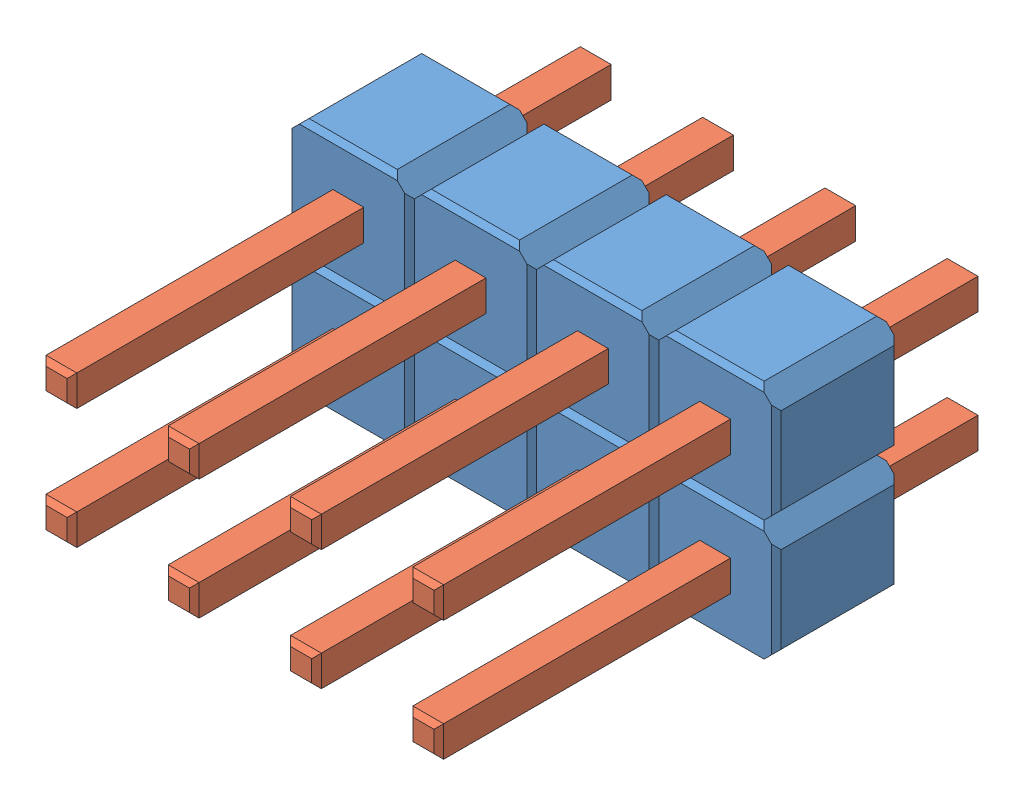
SolidWorks assembly Сборка14, configuration Default. Lengths in mm.
Overall size (10.16 5 11.3).
26 component instances, 2 part files, 2 mates.
Components (placement in the parent):
- pls_1x4_vert-1: pls_1x4_vert [Default] at (0.9139 -0.4526 1.8357) size (10.16 2.5 11.3)
  - pls_1_vert-1: pls_1_vert [Default] at (2.4589 -1.2488 -2.1291) size (2.54 2.5 11.3)
    - pin_plastic-1: pin_plastic [По умолчанию] at (1.6831 0.6372 -1.2507) size (2.54 2.5 2.54)
    - pin-1: pin [Default] at (-0.8569 0.6372 7.3493) x (1 0 0) z (0 1 0) size (0.64 11.3 0.64)
  - pls_1_vert-2: pls_1_vert [Default] at (-0.0811 -1.2488 -2.1291) size (2.54 2.5 11.3)
    - pin_plastic-1: pin_plastic [По умолчанию] at (1.6831 0.6372 -1.2507) size (2.54 2.5 2.54)
    - pin-1: pin [Default] at (-0.8569 0.6372 7.3493) x (1 0 0) z (0 1 0) size (0.64 11.3 0.64)
  - pls_1_vert-4: pls_1_vert [Default] at (-2.6211 -1.2488 -2.1291) size (2.54 2.5 11.3)
    - pin_plastic-1: pin_plastic [По умолчанию] at (1.6831 0.6372 -1.2507) size (2.54 2.5 2.54)
    - pin-1: pin [Default] at (-0.8569 0.6372 7.3493) x (1 0 0) z (0 1 0) size (0.64 11.3 0.64)
  - pls_1_vert-5: pls_1_vert [Default] at (-5.1611 -1.2488 -2.1291) size (2.54 2.5 11.3)
    - pin_plastic-1: pin_plastic [По умолчанию] at (1.6831 0.6372 -1.2507) size (2.54 2.5 2.54)
    - pin-1: pin [Default] at (-0.8569 0.6372 7.3493) x (1 0 0) z (0 1 0) size (0.64 11.3 0.64)
- pls_1x4_vert-2: pls_1x4_vert [Default] at (0.9139 2.0474 1.8357) size (10.16 2.5 11.3)
  - pls_1_vert-1: pls_1_vert [Default] at (2.4589 -1.2488 -2.1291) size (2.54 2.5 11.3)
    - pin_plastic-1: pin_plastic [По умолчанию] at (1.6831 0.6372 -1.2507) size (2.54 2.5 2.54)
    - pin-1: pin [Default] at (-0.8569 0.6372 7.3493) x (1 0 0) z (0 1 0) size (0.64 11.3 0.64)
  - pls_1_vert-2: pls_1_vert [Default] at (-0.0811 -1.2488 -2.1291) size (2.54 2.5 11.3)
    - pin_plastic-1: pin_plastic [По умолчанию] at (1.6831 0.6372 -1.2507) size (2.54 2.5 2.54)
    - pin-1: pin [Default] at (-0.8569 0.6372 7.3493) x (1 0 0) z (0 1 0) size (0.64 11.3 0.64)
  - pls_1_vert-4: pls_1_vert [Default] at (-2.6211 -1.2488 -2.1291) size (2.54 2.5 11.3)
    - pin_plastic-1: pin_plastic [По умолчанию] at (1.6831 0.6372 -1.2507) size (2.54 2.5 2.54)
    - pin-1: pin [Default] at (-0.8569 0.6372 7.3493) x (1 0 0) z (0 1 0) size (0.64 11.3 0.64)
  - pls_1_vert-5: pls_1_vert [Default] at (-5.1611 -1.2488 -2.1291) size (2.54 2.5 11.3)
    - pin_plastic-1: pin_plastic [По умолчанию] at (1.6831 0.6372 -1.2507) size (2.54 2.5 2.54)
    - pin-1: pin [Default] at (-0.8569 0.6372 7.3493) x (1 0 0) z (0 1 0) size (0.64 11.3 0.64)
Mates (geometry in assembly coordinates):
- Совпадение1: coincident: line of pls_1x4_vert-1/pls_1_vert-1/pin_plastic-1 through (3.4323 0.1858 0.8959) axis (0 0 -1); line of pls_1x4_vert-2/pls_1_vert-1/pin_plastic-1 through (3.4323 0.1858 0.8959) axis (0 0 -1)
- Совпадение2: coincident anti-aligned: line of pls_1x4_vert-1/pls_1_vert-1/pin_plastic-1 through (1.5994 0.1858 0.8959) axis (1 0 0); line of pls_1x4_vert-2/pls_1_vert-1/pin_plastic-1 through (3.4323 0.1858 0.8959) axis (-1 0 0)
